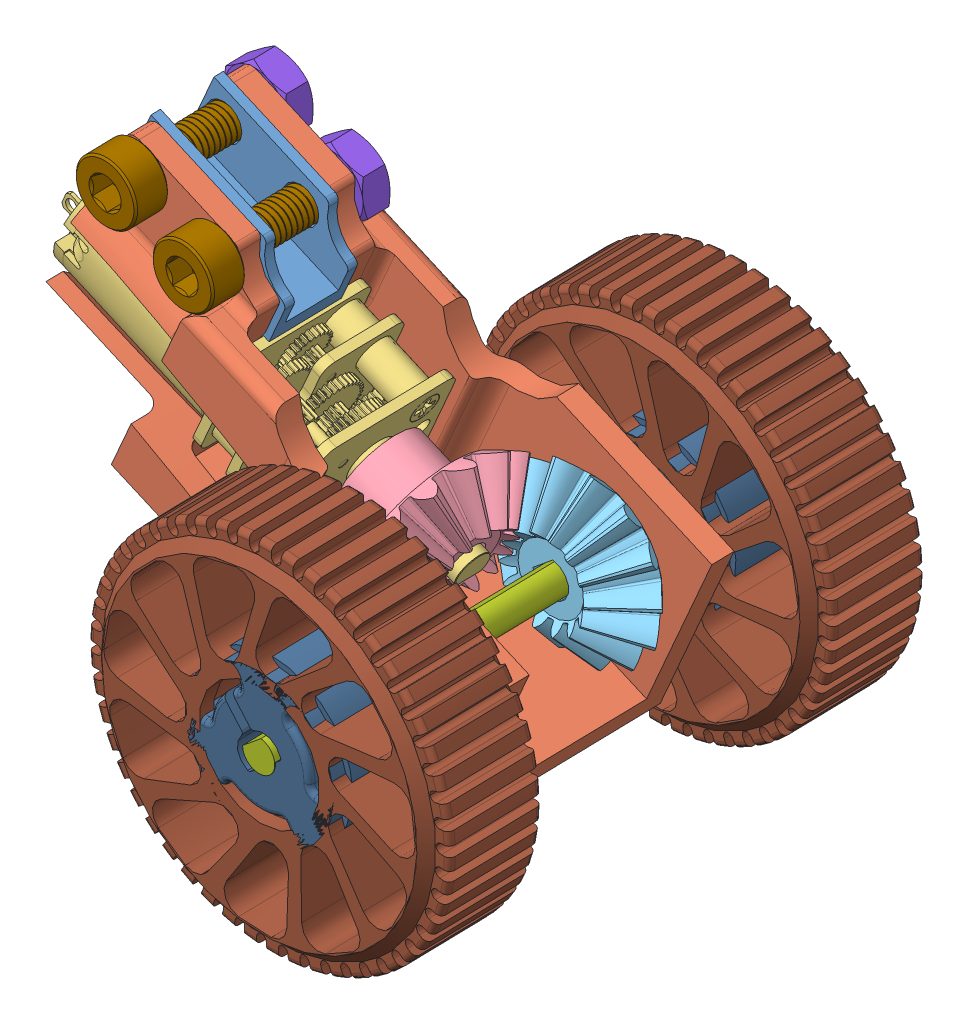
SolidWorks assembly Motor Housing 1, configuration Default. Lengths in mm.
Overall size (60.56 49.97 45.52).
18 component instances, 11 part files, 35 mates.
Components (placement in the parent):
- Motor Base2-2: Motor Base2 [Default] at (178.9236 -15.5749 -19.915) x (0 -0.022393 0.999749) z (-0.911742 0.410659 0.009198) size (6.5 8.02 14.6)
- Motor Mount-1: Motor Mount [Default] at (146.9767 -83.6029 -21.4387) x (0 -0.022393 0.999749) z (-0.911742 0.410659 0.009198) size (20.4 21.28 44.04)
- micro-metal-gearmotor-1: micro-metal-gearmotor [Default] at (181.6957 -25.8886 -20.146) x (0 -0.022393 0.999749) z (0.911742 -0.410659 -0.009198) size (12 10.04 35.8)
- With_convex-Metric - Straight miter gear 1M14T 20PA 5FW-1: With_convex-Metric - Straight miter gear 1M14T 20PA 5FW [Metric - Straight miter gear 1M14T 20PA 5FW ---14O10H8MD2N] at (194.6607 -31.7282 -20.2768) x (0.911742 -0.410659 -0.009198) z (0.410762 0.911514 0.020416) size (9.48 15.28 15.61)
- Metric - Straight miter gear 1M14T 20PA 5FW ---14O10H8MD2N-1: Metric - Straight miter gear 1M14T 20PA 5FW ---14O10H8MD2N [Metric - Straight miter gear 1M14T 20PA 5FW ---14O10H8MD2N] at (202.0011 -34.8541 -28.3998) x (0 -0.022393 0.999749) z (0.636021 -0.771478 -0.01728) size (5.08 15.28 15.61)
- 57155K427_Stainless Steel Ball Bearing-1: 57155K427_Stainless Steel Ball Bearing [57155K427] at (202.0011 -35.2247 -11.853) x (-0.918784 -0.394661 -0.00884) z (0 0.022393 -0.999749) size (8.1 8.1 2)
- 57155K427_Stainless Steel Ball Bearing-2: 57155K427_Stainless Steel Ball Bearing [57155K427] at (202.0011 -34.844 -28.8487) x (1 0.00067 0.000015) z (0 -0.022393 0.999749) size (8.1 8.1 2)
- Dshaftd3l40-1: Dshaftd3l40 [Default] at (202.0011 -35.0289 -20.5935) x (0 0.022393 -0.999749) z (0.771672 0.635862 0.014242) size (45 2.4 2.9)
- 90592A085_STEEL HEX NUT-1: 90592A085_STEEL HEX NUT [90592A085] at (181.5658 -14.9758 -26.3532) x (0.994973 0.100115 0.002242) z (0.100141 -0.994724 -0.02228) size (5.5 2.79 6.35)
- 91290A115_Black-Oxide Alloy Steel Socket Head Screw-1: 91290A115_Black-Oxide Alloy Steel Socket Head Screw [91290A115] at (181.5658 -15.0139 -24.6536) x (0.925422 0.378842 0.008485) z (0 0.022393 -0.999749) size (5.5 5.5 13.21)
- 90592A085_STEEL HEX NUT-2: 90592A085_STEEL HEX NUT [90592A085] at (174.7277 -11.8959 -26.2842) x (0.994973 0.100115 0.002242) z (0.100141 -0.994724 -0.02228) size (5.5 2.79 6.35)
- 91290A115_Black-Oxide Alloy Steel Socket Head Screw-2: 91290A115_Black-Oxide Alloy Steel Socket Head Screw [91290A115] at (174.7277 -11.9339 -24.5847) x (0.99706 0.076603 0.001716) z (0 0.022393 -0.999749) size (5.5 5.5 13.21)
- Compression Wheel v6-1: Compression Wheel v6 [Default] at (202.0011 -34.6716 -36.5468) x (0.771672 0.635862 0.014242) z (0.636021 -0.771478 -0.01728) size (32.5 12.03 32.5)
  - Outer Wheel v3-1: Outer Wheel v3 [Default] at origin size (14.3 12.03 14.3)
  - COmpression Wheel v5-1: COmpression Wheel v5 [Default] at origin size (32.5 10 32.5)
- Compression Wheel v6-2: Compression Wheel v6 [Default] at (202.0011 -35.3971 -4.1549) x (0.771672 0.635862 0.014242) z (-0.636021 0.771478 0.01728) size (32.5 12.03 32.5)
  - Outer Wheel v3-1: Outer Wheel v3 [Default] at origin size (14.3 12.03 14.3)
  - COmpression Wheel v5-1: COmpression Wheel v5 [Default] at origin size (32.5 10 32.5)
Mates (geometry in assembly coordinates):
- Coincident56: coincident aligned: plane of micro-metal-gearmotor-1 through (181.6957 -25.8886 -20.146) normal (0 -0.022393 0.999749); plane of Motor Mount-1 through (146.9767 -83.6029 -21.4387) normal (0 -0.022393 0.999749)
- Concentric35: concentric anti-aligned: cylinder of micro-metal-gearmotor-1 through (194.027 -31.4427 -20.2704) axis (0.911742 -0.410659 -0.009198) radius 1.5; cylinder of With_convex-Metric - Straight miter gear 1M14T 20PA 5FW-1 through (199.2943 -33.8152 -20.3236) axis (-0.911742 0.410659 0.009198) radius 1.6
- Parallel9: parallel anti-aligned: plane of micro-metal-gearmotor-1 through (198.608 -34.5776 -21.459) normal (-0.410762 -0.911514 -0.020416); plane of With_convex-Metric - Straight miter gear 1M14T 20PA 5FW-1 through (198.8425 -34.8179 -20.346) normal (0.410762 0.911514 0.020416)
- Distance1: distance = 0.1 mm anti-aligned: plane of micro-metal-gearmotor-1 through (190.5578 -29.8802 -20.2354) normal (0.911742 -0.410659 -0.009198); plane of With_convex-Metric - Straight miter gear 1M14T 20PA 5FW-1 through (190.649 -29.9212 -20.2364) normal (-0.911742 0.410659 0.009198)
- Coincident68: coincident: point of With_convex-Metric - Straight miter gear 1M14T 20PA 5FW-1; point of Metric - Straight miter gear 1M14T 20PA 5FW ---14O10H8MD2N-1
- Perpendicular1: perpendicular: line of With_convex-Metric - Straight miter gear 1M14T 20PA 5FW-1 through (185.5433 -27.6216 -20.1848) axis (0.911742 -0.410659 -0.009198); line of Metric - Straight miter gear 1M14T 20PA 5FW ---14O10H8MD2N-1 through (202.0011 -34.6302 -38.3973) axis (0 -0.022393 0.999749)
- GearMate1: gear = 3.4 : 3.2 mm: cylinder of Metric - Straight miter gear 1M14T 20PA 5FW ---14O10H8MD2N-1 through (202.0011 -34.9679 -23.319) axis (0 0.022393 -0.999749) radius 1.6; cylinder of With_convex-Metric - Straight miter gear 1M14T 20PA 5FW-1 through (199.2943 -33.8152 -20.3236) axis (-0.911742 0.410659 0.009198) radius 1.6
- Parallel12: parallel anti-aligned: plane of Motor Mount-1 through (166.5957 -10.1707 -26.2456) normal (0 -0.022393 0.999749); plane of Metric - Straight miter gear 1M14T 20PA 5FW ---14O10H8MD2N-1 through (202.0011 -34.8541 -28.3999) normal (0 0.022393 -0.999749)
- Parallel14: parallel anti-aligned: plane of Metric - Straight miter gear 1M14T 20PA 5FW ---14O10H8MD2N-1 through (201.3015 -34.1193 -23.2999) normal (0.636021 -0.771478 -0.01728); plane of Dshaftd3l40-1 through (201.3969 -34.7999 1.9173) normal (-0.636021 0.771478 0.01728)
- Coincident69: coincident anti-aligned: plane of Motor Mount-1 through (175.2636 -33.055 -11.6044) normal (0 -0.022393 0.999749); plane of 57155K427_Stainless Steel Ball Bearing-1 through (200.4023 -31.509 -11.5697) normal (0 0.022393 -0.999749)
- Concentric36: concentric aligned: cylinder of Motor Mount-1 through (202.0011 -35.2628 -10.1534) axis (0 0.022393 -0.999749) radius 3.6; cylinder of 57155K427_Stainless Steel Ball Bearing-1 through (202.0011 -35.2247 -11.853) axis (0 0.022393 -0.999749) radius 1.5
- Coincident70: coincident anti-aligned: plane of Motor Mount-1 through (182.2465 -17.1697 -28.6529) normal (0 0.022393 -0.999749); plane of 57155K427_Stainless Steel Ball Bearing-2 through (201.9984 -30.7906 -28.958) normal (0 -0.022393 0.999749)
- Concentric37: concentric anti-aligned: cylinder of Motor Mount-1 through (202.0011 -35.2628 -10.1534) axis (0 0.022393 -0.999749) radius 3.6; cylinder of 57155K427_Stainless Steel Ball Bearing-2 through (202.0011 -34.844 -28.8487) axis (0 -0.022393 0.999749) radius 1.5
- Concentric38: concentric anti-aligned: cylinder of 57155K427_Stainless Steel Ball Bearing-2 through (202.0011 -34.844 -28.8487) axis (0 -0.022393 0.999749) radius 1.5; cylinder of Dshaftd3l40-1 through (202.0011 -35.5328 1.9009) axis (0 0.022393 -0.999749) radius 1.45
- Concentric94: concentric aligned: cylinder of Motor Mount-1 through (174.7277 -12.2082 -12.3387) axis (0 0.022393 -0.999749) radius 1.51; cylinder of Motor Base2-2 through (174.7277 -12.1131 -16.5867) axis (0 0.022393 -0.999749) radius 1.625
- Concentric95: concentric aligned: cylinder of Motor Mount-1 through (181.5658 -15.2882 -12.4077) axis (0 0.022393 -0.999749) radius 1.51; cylinder of Motor Base2-2 through (181.5658 -15.193 -16.6557) axis (0 0.022393 -0.999749) radius 1.625
- Coincident152: coincident aligned: plane of Motor Mount-1 through (146.9767 -83.6029 -21.4387) normal (0 -0.022393 0.999749); plane of Motor Base2-2 through (178.9236 -15.5749 -19.915) normal (0 -0.022393 0.999749)
- Concentric103: concentric aligned: cone of 90592A085_STEEL HEX NUT-1 through (181.5658 -15.0027 -25.1535) axis (0 0.022393 -0.999749); cone of 91290A115_Black-Oxide Alloy Steel Socket Head Screw-1 through (181.5658 -15.0139 -24.6536) axis (0 0.022393 -0.999749)
- Coincident157: coincident anti-aligned: plane of Motor Mount-1 through (149.5354 -5.4141 -24.9388) normal (0 0.022393 -0.999749); plane of 90592A085_STEEL HEX NUT-1 through (178.6706 -13.6987 -25.1243) normal (0 -0.022393 0.999749)
- Parallel30: parallel aligned: plane of Motor Base2-2 through (173.917 -8.9956 -16.5168) normal (0.410762 0.911514 0.020416); plane of 90592A085_STEEL HEX NUT-1 through (184.143 -13.148 -25.112) normal (0.410762 0.911514 0.020416)
- Concentric102: concentric aligned: cone of 91290A115_Black-Oxide Alloy Steel Socket Head Screw-1 through (181.5658 -15.0139 -24.6536) axis (0 0.022393 -0.999749); cylinder of Motor Base2-2 through (181.5658 -15.193 -16.6557) axis (0 0.022393 -0.999749) radius 1.625
- Coincident156: coincident anti-aligned: plane of Motor Mount-1 through (149.5354 -5.6492 -14.4414) normal (0 -0.022393 0.999749); plane of 91290A115_Black-Oxide Alloy Steel Socket Head Screw-1 through (181.5658 -15.2378 -14.6562) normal (0 0.022393 -0.999749)
- Concentric105: concentric aligned: cone of 90592A085_STEEL HEX NUT-2 through (174.7277 -11.9227 -25.0845) axis (0 0.022393 -0.999749); cone of 91290A115_Black-Oxide Alloy Steel Socket Head Screw-2 through (174.7277 -11.9339 -24.5847) axis (0 0.022393 -0.999749)
- Coincident160: coincident anti-aligned: plane of Motor Mount-1 through (149.5354 -5.4141 -24.9388) normal (0 0.022393 -0.999749); plane of 90592A085_STEEL HEX NUT-2 through (171.8326 -10.6187 -25.0553) normal (0 -0.022393 0.999749)
- Parallel31: parallel aligned: plane of Motor Base2-2 through (173.917 -8.9956 -16.5168) normal (0.410762 0.911514 0.020416); plane of 90592A085_STEEL HEX NUT-2 through (177.3049 -10.0681 -25.043) normal (0.410762 0.911514 0.020416)
- Coincident159: coincident anti-aligned: plane of Motor Mount-1 through (149.5354 -5.6492 -14.4414) normal (0 -0.022393 0.999749); plane of 91290A115_Black-Oxide Alloy Steel Socket Head Screw-2 through (174.7277 -12.1579 -14.5872) normal (0 0.022393 -0.999749)
- Concentric104: concentric aligned: cylinder of Motor Base2-2 through (174.7277 -12.1131 -16.5867) axis (0 0.022393 -0.999749) radius 1.625; cone of 91290A115_Black-Oxide Alloy Steel Socket Head Screw-2 through (174.7277 -11.9339 -24.5847) axis (0 0.022393 -0.999749)
- Coincident254: coincident anti-aligned: plane of Metric - Straight miter gear 1M14T 20PA 5FW ---14O10H8MD2N-1 through (202.0011 -34.8541 -28.3999) normal (0 0.022393 -0.999749); plane of Bevel Gear Spacer-1 through (201.9391 -35.197 -31.7523) normal (0 -0.022393 0.999749)
- Concentric157: concentric anti-aligned: cylinder of Dshaftd3l40-1 through (202.0011 -35.5328 1.9009) axis (0 0.022393 -0.999749) radius 1.45; cylinder of Bevel Gear Spacer-1 through (201.9391 -35.1589 -33.4519) axis (0 -0.022393 0.999749) radius 1.6
- Coincident255: coincident anti-aligned: plane of Motor Mount-1 through (205.7811 -109.8607 -32.2294) normal (0 0.022393 -0.999749); plane of Compression Wheel v6-1/Outer Wheel v3-1 through (199.7751 -32.1058 -30.4878) normal (0 -0.022393 0.999749)
- Concentric163: concentric anti-aligned: cylinder of Dshaftd3l40-1 through (202.0011 -35.5328 1.9009) axis (0 0.022393 -0.999749) radius 1.45; cylinder of Compression Wheel v6-1/Outer Wheel v3-1 through (202.0011 -34.8423 -28.9258) axis (0 -0.022393 0.999749) radius 7.15
- Parallel35: parallel anti-aligned: plane of Dshaftd3l40-1 through (201.3969 -34.7999 1.9173) normal (-0.636021 0.771478 0.01728); plane of Compression Wheel v6-1/Outer Wheel v3-1 through (200.0561 -35.0388 -42.5565) normal (0.636021 -0.771478 -0.01728)
- Concentric164: concentric aligned: cylinder of Dshaftd3l40-1 through (202.0011 -35.5328 1.9009) axis (0 0.022393 -0.999749) radius 1.45; cylinder of Compression Wheel v6-2/Outer Wheel v3-1 through (202.0011 -35.2264 -11.7759) axis (0 0.022393 -0.999749) radius 3.5
- Parallel36: parallel aligned: plane of Dshaftd3l40-1 through (201.3969 -34.7999 1.9173) normal (-0.636021 0.771478 0.01728); plane of Compression Wheel v6-2/Outer Wheel v3-1 through (201.1373 -37.3445 1.8029) normal (-0.636021 0.771478 0.01728)
- Coincident259: coincident anti-aligned: plane of Motor Mount-1 through (205.7811 -110.3176 -11.8345) normal (0 -0.022393 0.999749); plane of Compression Wheel v6-2/Outer Wheel v3-1 through (204.2272 -37.963 -10.2139) normal (0 0.022393 -0.999749)
